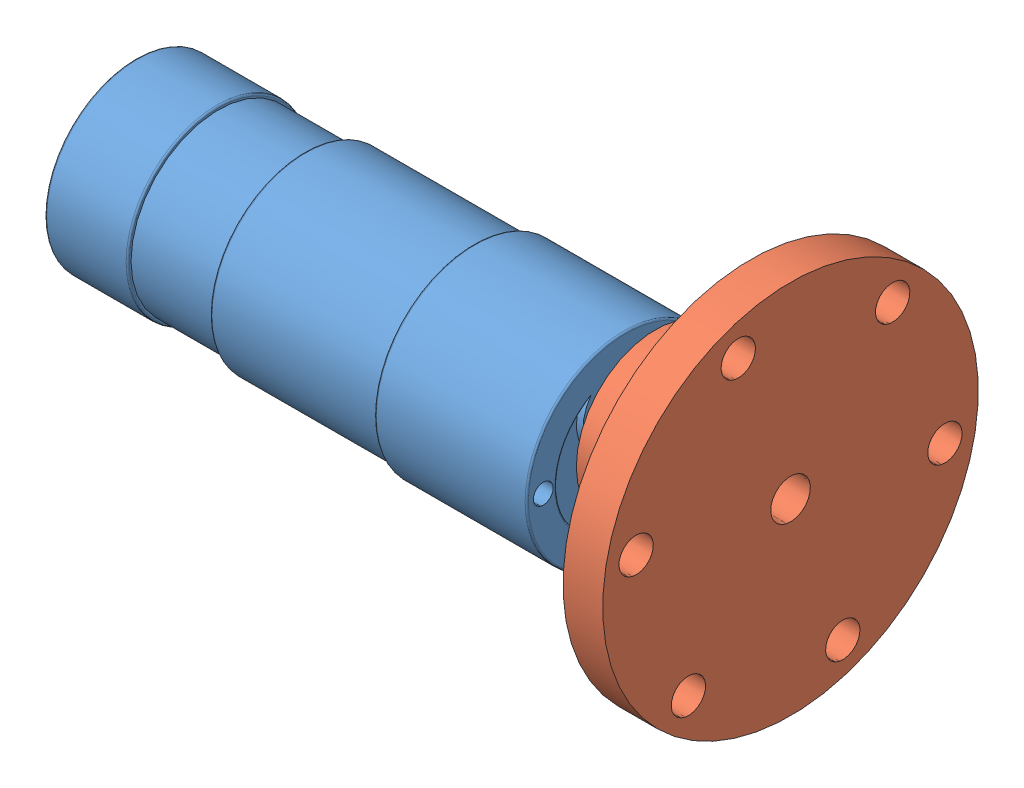
SolidWorks assembly Drivetrain Left Assem, configuration Default. Lengths in mm.
Overall size (99 66.25 66.25).
2 component instances, 2 part files, 2 mates.
Components (placement in the parent):
- Devantech EMG30-1: Devantech EMG30 [Default] at (-103.7925 14.0553 22.3721) size (86.6 30 30)
- Wheel Hub-1: Wheel Hub [Default] at (-4.7925 19.5553 22.3721) x (0 0.183359 0.983046) z (-1 0 0) size (56.8 56.8 22.4)
Mates (geometry in assembly coordinates):
- Concentric1: concentric: cylinder of Devantech EMG30-1 through (-17.1925 19.5553 22.3721) axis (-1 0 0) radius 2.5; cylinder of Wheel Hub-1 through (11.325 19.5553 22.3721) axis (-1 0 0) radius 3
- Coincident2: coincident anti-aligned: plane of Devantech EMG30-1 through (-27.1925 14.0553 22.3721) normal (1 0 0); plane of Wheel Hub-1 through (-27.1925 19.5553 22.3721) normal (-1 0 0)
